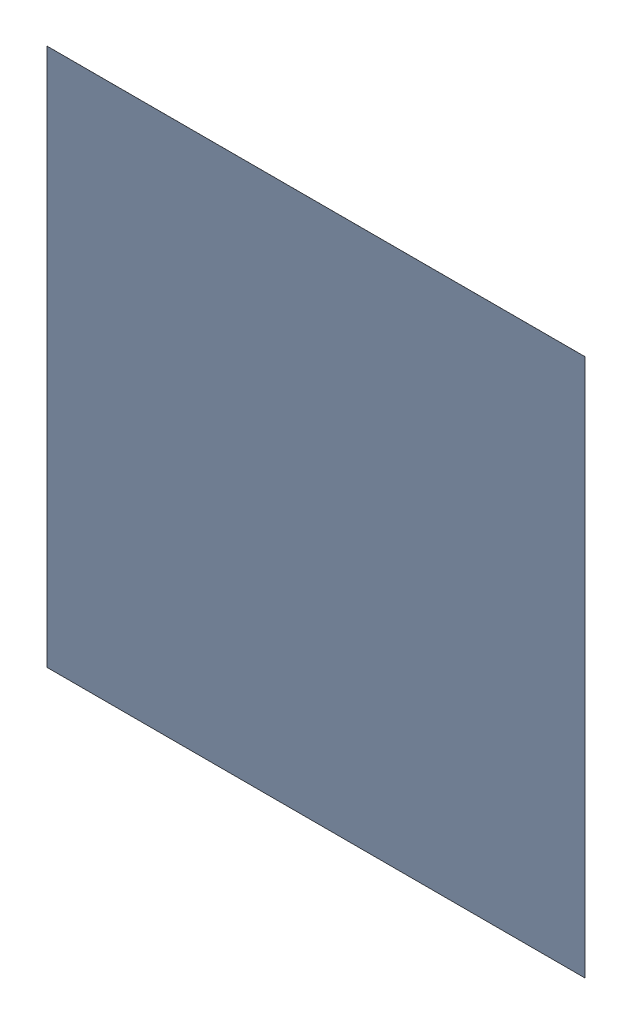
SolidWorks assembly X1, configuration Standard. Lengths in mm.
Overall size (0.05 0.05 0).
2 component instances, 1 part files, 0 mates.
Components (placement in the parent):
- 6269211456-1: 6269211456 [Standard] at (4.5 -23.5 0) x (0 1 0) z (0 0 1) size (0.05 0.05 0)
  - Extruded-3-1: Extruded-3 [Standard] at origin size (0.05 0.05 0)
